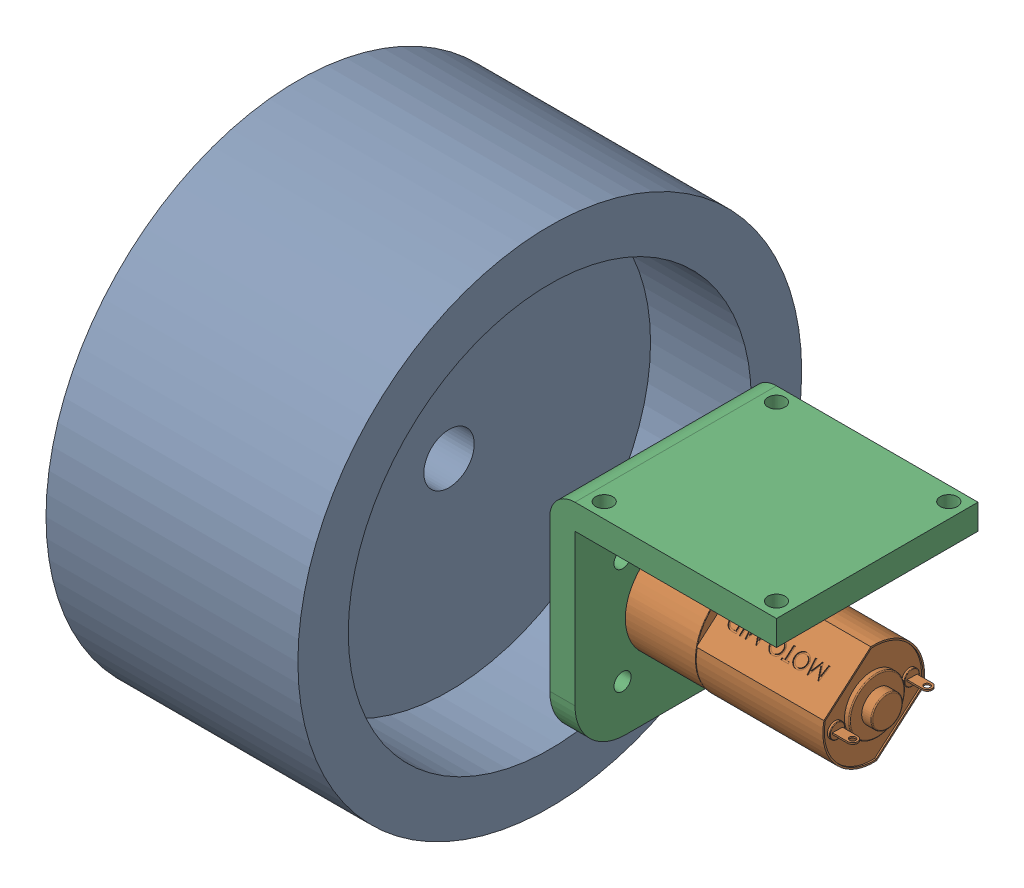
SolidWorks assembly roda, configuration Default. Lengths in mm.
Overall size (118.5 100 100).
3 component instances, 3 part files, 4 mates.
Components (placement in the parent):
- wheelonly-1: wheelonly [Default] at (638.9423 879.927 1272.101) size (50 100 100)
- moto MID nap du-1: moto MID nap du [Default] at (702.9423 879.927 1272.101) x (-1 0 0) z (0 0.999637 -0.02693) size (58.5 20.2 20.2)
- bracket-2: bracket [Default] at (708.9423 904.927 1272.101) x (-1 0 0) z (0 0 1) size (45 45 40)
Mates (geometry in assembly coordinates):
- Concentric1: concentric anti-aligned: cylinder of wheelonly-1 through (663.9423 879.927 1272.101) axis (-1 0 0) radius 5; cylinder of moto MID nap du-1 through (702.9423 879.927 1272.101) axis (1 0 0) radius 2
- Concentric2: concentric aligned: cylinder of moto MID nap du-1 through (702.9423 879.927 1272.101) axis (1 0 0) radius 10; cylinder of bracket-2 through (683.9423 879.927 1272.101) axis (1 0 0) radius 10
- Distance1: distance = 40 mm anti-aligned: plane of bracket-2 through (683.9423 904.927 1272.101) normal (-1 0 0); plane of wheelonly-1 through (643.9423 879.927 1272.101) normal (1 0 0)
- Coincident1: coincident aligned: plane of moto MID nap du-1 through (683.9423 869.9306 1272.3703) normal (-1 0 0); plane of bracket-2 through (683.9423 904.927 1272.101) normal (-1 0 0)
